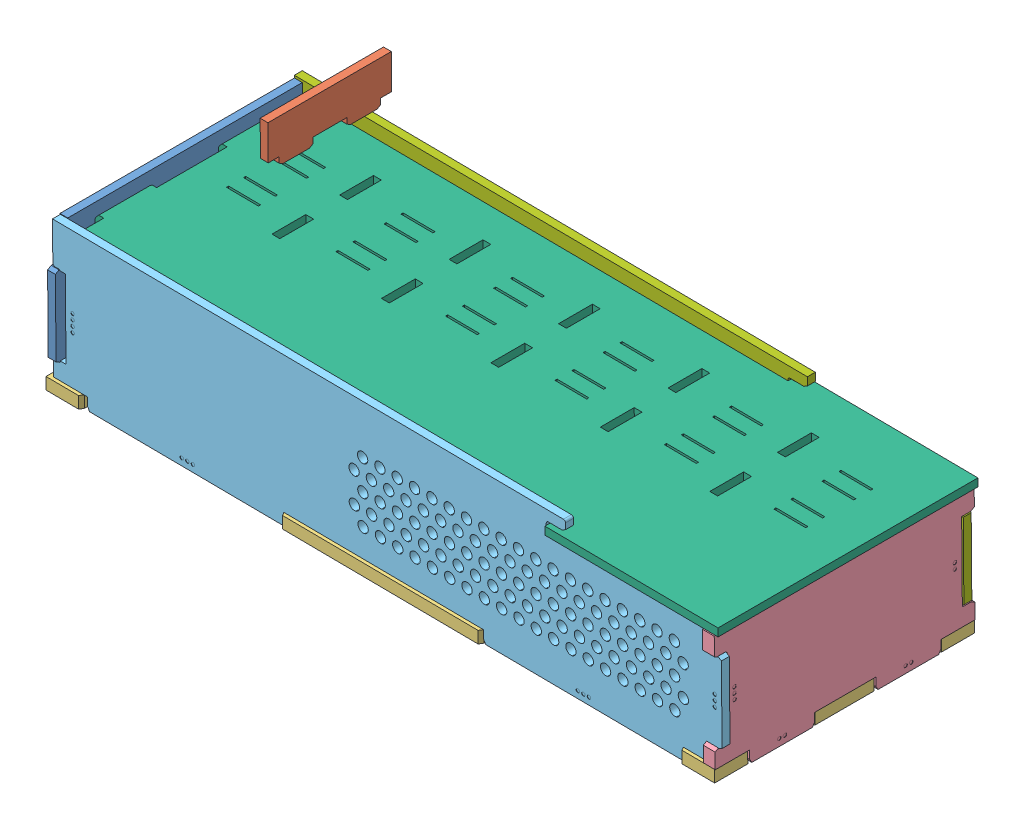
SolidWorks assembly Assem1, configuration Default. Lengths in mm.
Overall size (247.14 88.82 96.22).
7 component instances, 7 part files, 18 mates.
Components (placement in the parent):
- Back Wall, Laser Cut Box, Masonite (0.17in), Type 1-1: Back Wall, Laser Cut Box, Masonite (0.17in), Type 1 [Default] at (-83.9263 -4.101 178.6299) x (0.008727 0.008725 -0.999924) z (-0.000152 -0.999962 -0.008727) size (93.65 2.86 54.32)
- DIVIDER-1: DIVIDER [Default] at (-40.8029 48.3978 166.5166) x (-0.008727 -0.008725 0.999924) z (-0.999962 0.000228 -0.008726) size (44.45 15.56 2.86)
- Floor,  Laser Cut Box, Masonite (0.17in), Type 1-1: Floor,  Laser Cut Box, Masonite (0.17in), Type 1 [Default] at (37.4159 -33.4428 179.1154) x (0.999962 -0.000228 0.008726) z (-0.008727 -0.008725 0.999924) size (245.11 4.32 93.65)
- Front Wall, Laser Cut Box, Masonite (0.17in), Type 1-1: Front Wall, Laser Cut Box, Masonite (0.17in), Type 1 [Default] at (160.2247 -4.154 180.4429) x (-0.008727 -0.008725 0.999924) z (-0.000152 -0.999962 -0.008727) size (93.65 4.32 46.57)
- Left Wall, Laser Cut Box, Masonite (0.17in), Type 1-1: Left Wall, Laser Cut Box, Masonite (0.17in), Type 1 [Default] at (38.6346 -4.4994 222.1444) x (0.999962 -0.000228 0.008726) z (-0.000152 -0.999962 -0.008727) size (245.11 2.86 54.32)
- Lid_v2, Laser Cut Box, Masonite (0.17in), Type 1-1: Lid_v2, Laser Cut Box, Masonite (0.17in), Type 1 [Default] at (38.6333 13.13 179.0879) x (-0.999962 0.000228 -0.008726) z (0.008727 0.008725 -0.999924) size (245.11 2.86 93.65)
- Right Wall, Laser Cut Box, Masonite (0.17in), Type 1-1: Right Wall, Laser Cut Box, Masonite (0.17in), Type 1 [Default] at (38.136 -3.728 133.7575) x (0.999962 -0.000228 0.008726) z (-0.000152 -0.999962 -0.008727) size (245.11 2.86 54.32)
Mates (geometry in assembly coordinates):
- Coincident1: coincident anti-aligned: plane of Floor,  Laser Cut Box, Masonite (0.17in), Type 1-1 through (155.8031 -33.5702 191.524) normal (0.999962 -0.000228 0.008726); plane of Front Wall, Laser Cut Box, Masonite (0.17in), Type 1-1 through (155.9068 -4.153 180.4052) normal (-0.999962 0.000228 -0.008726)
- Coincident2: coincident aligned: plane of Floor,  Laser Cut Box, Masonite (0.17in), Type 1-1 through (37.4159 -33.4428 179.1154) normal (-0.000152 -0.999962 -0.008727); plane of Front Wall, Laser Cut Box, Masonite (0.17in), Type 1-1 through (132.0254 -33.5609 190.999) normal (-0.000152 -0.999962 -0.008727)
- Coincident3: coincident aligned: plane of Floor,  Laser Cut Box, Masonite (0.17in), Type 1-1 through (-84.7251 -28.6884 131.2608) normal (0.008727 0.008725 -0.999924); plane of Front Wall, Laser Cut Box, Masonite (0.17in), Type 1-1 through (156.3193 21.2546 133.8004) normal (0.008727 0.008725 -0.999924)
- Coincident4: coincident anti-aligned: plane of Back Wall, Laser Cut Box, Masonite (0.17in), Type 1-1 through (-81.0689 -4.1016 178.6549) normal (0.999962 -0.000228 0.008726); plane of Floor,  Laser Cut Box, Masonite (0.17in), Type 1-1 through (-81.1699 -33.516 189.4562) normal (-0.999962 0.000228 -0.008726)
- Coincident5: coincident aligned: plane of Back Wall, Laser Cut Box, Masonite (0.17in), Type 1-1 through (-57.1964 -33.3275 167.5493) normal (-0.000152 -0.999962 -0.008727); plane of Floor,  Laser Cut Box, Masonite (0.17in), Type 1-1 through (37.4159 -33.4428 179.1154) normal (-0.000152 -0.999962 -0.008727)
- Coincident6: coincident anti-aligned: plane of Back Wall, Laser Cut Box, Masonite (0.17in), Type 1-1 through (-57.3894 -33.5204 189.6637) normal (0.008727 0.008725 -0.999924); plane of Floor,  Laser Cut Box, Masonite (0.17in), Type 1-1 through (-85.2337 -33.5151 189.4207) normal (-0.008727 -0.008725 0.999924)
- Coincident8: coincident anti-aligned: plane of Floor,  Laser Cut Box, Masonite (0.17in), Type 1-1 through (146.858 -33.8775 226.897) normal (-0.999962 0.000228 -0.008726); plane of Left Wall, Laser Cut Box, Masonite (0.17in), Type 1-1 through (146.2283 -34.506 299.0488) normal (0.999962 -0.000228 0.008726)
- Coincident9: coincident aligned: plane of Floor,  Laser Cut Box, Masonite (0.17in), Type 1-1 through (37.4159 -33.4428 179.1154) normal (-0.000152 -0.999962 -0.008727); plane of Left Wall, Laser Cut Box, Masonite (0.17in), Type 1-1 through (-72.2034 -34.4561 297.1428) normal (-0.000152 -0.999962 -0.008727)
- Coincident16: coincident: plane of Floor,  Laser Cut Box, Masonite (0.17in), Type 1-1 through (37.4159 -33.4428 179.1154) normal (-0.000152 -0.999962 -0.008727); plane of Right Wall, Laser Cut Box, Masonite (0.17in), Type 1-1 through (-72.3874 -33.3703 172.7156) normal (-0.000152 -0.999962 -0.008727)
- Coincident17: coincident: plane of Floor,  Laser Cut Box, Masonite (0.17in), Type 1-1 through (1.2076 -33.0269 131.9729) normal (-0.999962 0.000228 -0.008726); plane of Right Wall, Laser Cut Box, Masonite (0.17in), Type 1-1 through (0.8464 -33.387 173.3547) normal (0.999962 -0.000228 0.008726)
- Coincident18: coincident anti-aligned: plane of Back Wall, Laser Cut Box, Masonite (0.17in), Type 1-1 through (-80.7815 13.4344 146.2959) normal (-0.008727 -0.008725 0.999924); plane of Lid_v2, Laser Cut Box, Masonite (0.17in), Type 1-1 through (-83.6399 13.434 146.271) normal (0.008727 0.008725 -0.999924)
- Coincident19: coincident anti-aligned: plane of Back Wall, Laser Cut Box, Masonite (0.17in), Type 1-1 through (-80.9611 13.2549 166.8683) normal (0.000152 0.999962 0.008727); plane of Lid_v2, Laser Cut Box, Masonite (0.17in), Type 1-1 through (38.6333 13.13 179.0879) normal (-0.000152 -0.999962 -0.008727)
- Parallel5: parallel: plane of Lid_v2, Laser Cut Box, Masonite (0.17in), Type 1-1 through (-83.538 13.5359 134.5951) normal (0.008727 0.008725 -0.999924); plane of Right Wall, Laser Cut Box, Masonite (0.17in), Type 1-1 through (38.4256 -3.4384 100.5745) normal (-0.008727 -0.008725 0.999924)
- Coincident20: coincident aligned: plane of Back Wall, Laser Cut Box, Masonite (0.17in), Type 1-1 through (-83.9263 -4.101 178.6299) normal (-0.999962 0.000228 -0.008726); plane of Lid_v2, Laser Cut Box, Masonite (0.17in), Type 1-1 through (-84.3252 15.6068 224.8665) normal (-0.999962 0.000228 -0.008726)
- Coincident22: coincident anti-aligned: plane of DIVIDER-1 through (-43.6603 48.3985 166.4917) normal (-0.999962 0.000228 -0.008726); plane of Lid_v2, Laser Cut Box, Masonite (0.17in), Type 1-1 through (-43.8252 13.0956 184.4716) normal (0.999962 -0.000228 0.008726)
- Coincident23: coincident anti-aligned: plane of DIVIDER-1 through (-43.5021 39.3509 148.1247) normal (0.008727 0.008725 -0.999924); plane of Lid_v2, Laser Cut Box, Masonite (0.17in), Type 1-1 through (-43.506 13.4147 147.8984) normal (-0.008727 -0.008725 0.999924)
- Coincident24: coincident anti-aligned: plane of Floor,  Laser Cut Box, Masonite (0.17in), Type 1-1 through (-72.8081 -33.7918 220.9162) normal (-0.008727 -0.008725 0.999924); plane of Left Wall, Laser Cut Box, Masonite (0.17in), Type 1-1 through (38.6346 -4.4994 222.1444) normal (0.008727 0.008725 -0.999924)
- Coincident25: coincident anti-aligned: plane of Floor,  Laser Cut Box, Masonite (0.17in), Type 1-1 through (-72.0617 -33.0456 135.3976) normal (0.008727 0.008725 -0.999924); plane of Right Wall, Laser Cut Box, Masonite (0.17in), Type 1-1 through (38.111 -3.7529 136.6148) normal (-0.008727 -0.008725 0.999924)
